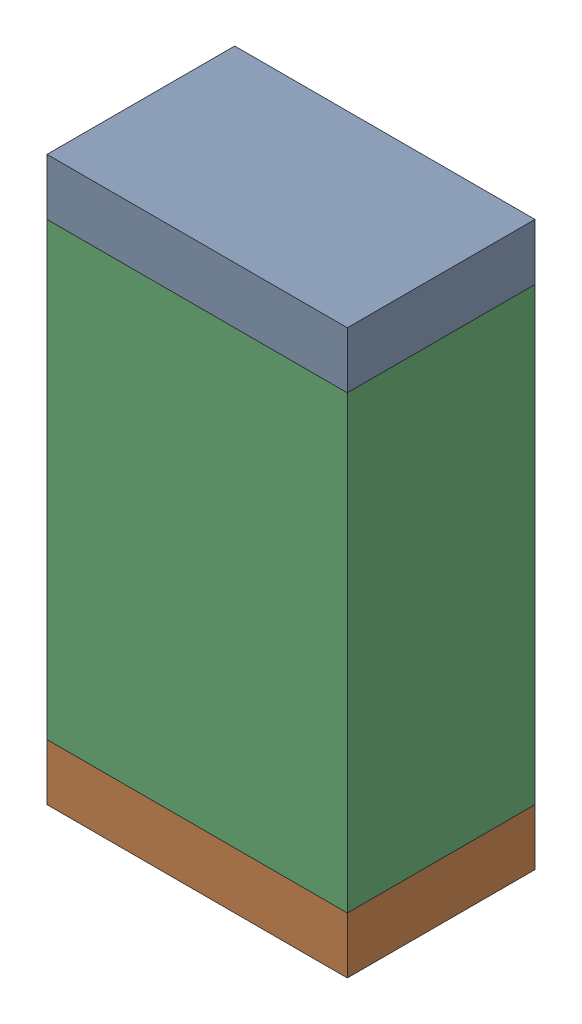
SolidWorks assembly R28, configuration Default. Lengths in mm.
Overall size (0.8 1.5 0.5).
6 component instances, 2 part files, 0 mates.
Components (placement in the parent):
- 810156592-1: 810156592 [Default] at (116.45 48.875 0) size (0.8 0.15 0.5)
  - Extruded_7-1: Extruded_7 [Default] at origin size (0.8 0.15 0.5)
- 810156592-2: 810156592 [Default] at (116.45 47.525 0) size (0.8 0.15 0.5)
  - Extruded_7-1: Extruded_7 [Default] at origin size (0.8 0.15 0.5)
- 810156976-1: 810156976 [Default] at (116.45 48.2 0) size (0.8 1.2 0.5)
  - Extruded_6-1: Extruded_6 [Default] at origin size (0.8 1.2 0.5)
